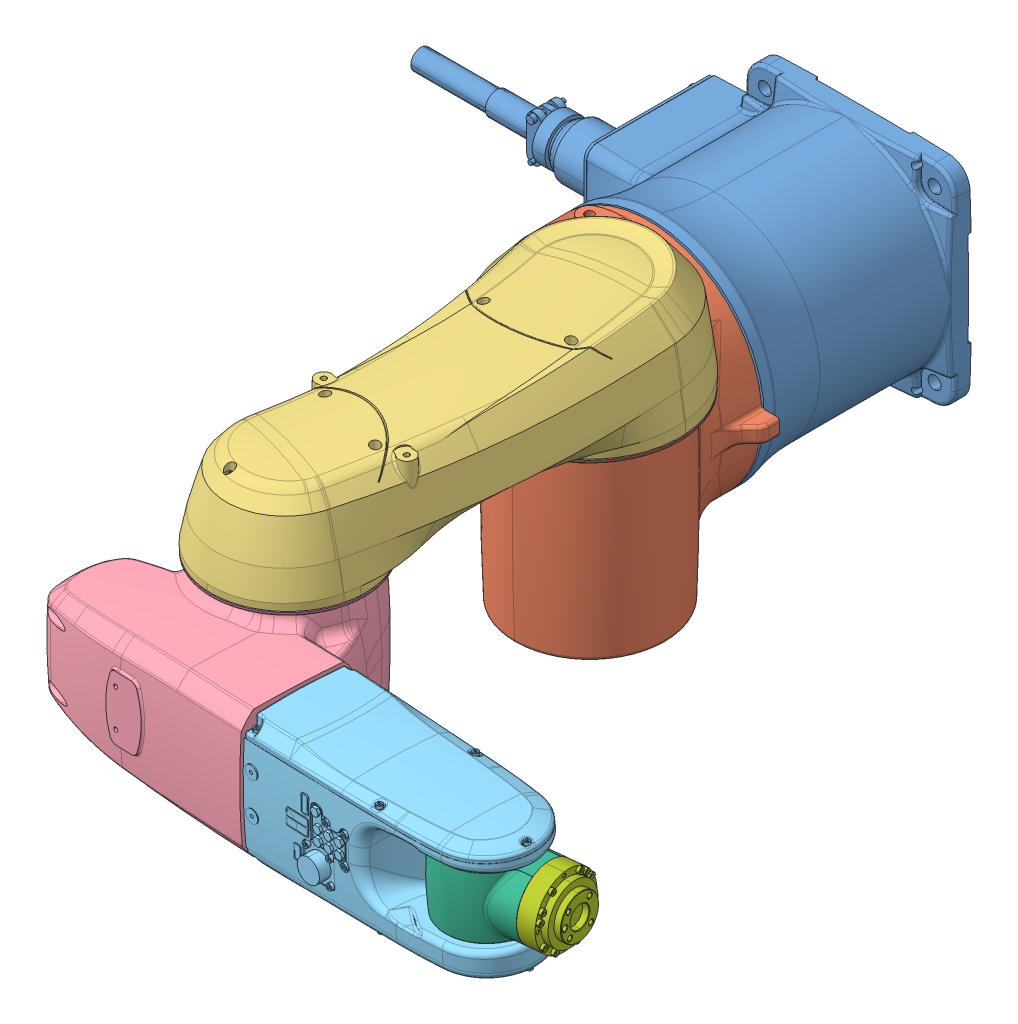
SolidWorks assembly ROBOT, configuration Default. Lengths in mm.
Overall size (766.2 290.85 772.46).
7 component instances, 7 part files, 8 mates.
Components (placement in the parent):
- base-4: base [Default] at origin size (447.67 231.25 211.63)
- link1-1: link1 [Default] at (0 0 185) x (0.999996 0.002774 0) z (0 0 1) size (274.13 220.02 235)
- link2-1: link2 [Default] at (74.8485 54.7078 335) x (0.998538 0.002774 0.053978) z (-0.053978 -0.000152 0.998542) size (173.33 125.76 428.87)
- link3-1: link3 [Default] at (60.2897 49.1674 604.6064) x (-0.998977 -0.002771 -0.045133) z (-0.045133 -0.000125 0.998981) size (223.06 161.04 216.11)
- link4-1: link4 [Default] at (144.2737 0.4002 698.4863) x (-0.998977 -0.002771 -0.045133) z (-0.045081 -0.016415 0.998848) size (254.5 122.01 117.22)
- link5_test1-1: link5_test1 [Default] at (351.1286 -18.0235 707.5196) x (0.995089 0.005101 -0.098851) z (0.09892 -0.015846 0.994969) size (92.95 71.21 81.91)
- link5_test2-2: link5_test2 [Default] at (430.609 1.4151 699.3175) x (0.995089 0.005101 -0.098851) z (0.098982 -0.054733 0.993583) size (38 65 65)
Mates (geometry in assembly coordinates):
- Coincident13: coincident anti-aligned: circle of base-4; circle of link1-1
- Coincident14: coincident anti-aligned: circle of link1-1; circle of link2-1
- Coincident16: coincident anti-aligned: circle of link3-1; circle of link4-1
- Concentric4: concentric aligned: cylinder of link2-1 through (60.2897 49.1674 604.6064) axis (-0.002774 0.999996 0) radius 25; cylinder of link3-1 through (60.2897 49.1674 604.6064) axis (-0.002774 0.999996 0) radius 25
- Coincident27: coincident anti-aligned: plane of link2-1 through (60.2897 49.1674 604.6064) normal (0.002774 -0.999996 0); plane of link3-1 through (60.2897 49.1674 604.6064) normal (-0.002774 0.999996 0)
- Coincident28: coincident anti-aligned: circle of link4-1; circle of link5_test1-1
- Concentric5: concentric aligned: cylinder of link5_test1-1 through (392.8557 1.1881 703.6771) axis (0.995089 0.005101 -0.098851) radius 3; cylinder of link5_test2-2 through (392.8557 1.1881 703.6771) axis (0.995089 0.005101 -0.098851) radius 3
- Coincident30: coincident anti-aligned: plane of link5_test1-1 through (403.915 -25.6453 712.4593) normal (0.995089 0.005101 -0.098851); plane of link5_test2-2 through (399.5959 35.5214 672.1367) normal (-0.995089 -0.005101 0.098851)
